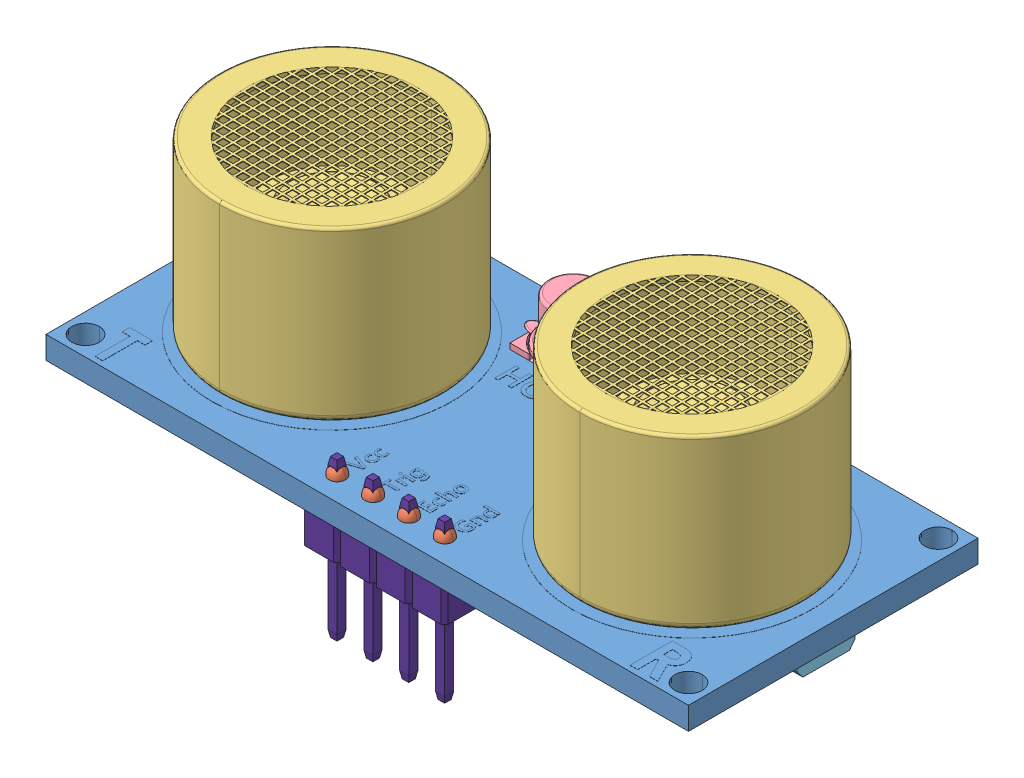
SolidWorks assembly HC-SR04, configuration Default. Lengths in mm.
Overall size (45.5 21.95 20.5).
46 component instances, 17 part files, 0 mates.
Components (placement in the parent):
- HC-SR04.STEP-1: HC-SR04.STEP [Default] at origin size (45.5 21.95 20.5)
  - HC-SR04board.STEP-1: HC-SR04board.STEP [Default] at origin size (45.5 1.61 20.5)
  - solder.STEP-1: solder.STEP [Default] at (-3.8014 1.6 8.5727) size (1.17 0.65 1.17)
  - solder.STEP-2: solder.STEP [Default] at (-1.2614 1.6 8.5727) size (1.17 0.65 1.17)
  - solder.STEP-3: solder.STEP [Default] at (1.2786 1.6 8.5727) size (1.17 0.65 1.17)
  - solder.STEP-4: solder.STEP [Default] at (3.8186 1.6 8.5727) size (1.17 0.65 1.17)
  - Emitter.STEP-1: Emitter.STEP [Default] at (-12.75 1.6 0) size (15.9 15.2 15.9)
  - Emitter.STEP-2: Emitter.STEP [Default] at (12.75 1.6 0) size (15.9 15.2 15.9)
  - CrystalOscillator.STEP-1: CrystalOscillator.STEP [Default] at (0 1.6 -7.5) size (13.3 6.4 4.5)
  - solder.STEP-5: solder.STEP [Default] at (-2.0167 0 -7.5286) x (-0.837169 0 -0.546944) z (-0.546944 0 0.837169) size (1.17 0.65 1.17)
  - solder.STEP-6: solder.STEP [Default] at (1.9833 0 -7.5286) x (-0.837169 0 -0.546944) z (-0.546944 0 0.837169) size (1.17 0.65 1.17)
  - smdChip14pin.STEP-1: smdChip14pin.STEP [Default] at (22.25 -0.725 0) x (0 0 -1) z (-1 0 0) size (7.3 1.22 8.75)
  - smdChip14pin.STEP-2: smdChip14pin.STEP [Default] at (4.375 -0.725 0) x (0 0 -1) z (-1 0 0) size (7.3 1.22 8.75)
  - smdChip16pin.STEP-1: smdChip16pin.STEP [Default] at (-18.6 -0.725 5) x (1 0 0) z (0 0 -1) size (7.3 1.22 10)
  - smdceramiccapacitor.STEP-1: smdceramiccapacitor.STEP [Default] at (17.8499 0 -5.5522) x (0 0 -1) z (-1 0 0) size (2.52 0.61 1.3)
  - smdceramiccapacitor.STEP-2: smdceramiccapacitor.STEP [Default] at (17.8499 0 5.585) x (0 0 -1) z (-1 0 0) size (2.52 0.61 1.3)
  - smdceramiccapacitor.STEP-3: smdceramiccapacitor.STEP [Default] at (15.2359 0 8.7006) x (-1 0 0) z (0 0 1) size (2.52 0.61 1.3)
  - smdceramiccapacitor.STEP-4: smdceramiccapacitor.STEP [Default] at (8.3844 0 0.0383) x (-1 0 0) z (0 0 1) size (2.52 0.61 1.3)
  - smdceramiccapacitor.STEP-5: smdceramiccapacitor.STEP [Default] at (8.3844 0 -4.7577) x (-1 0 0) z (0 0 1) size (2.52 0.61 1.3)
  - smdceramiccapacitor.STEP-6: smdceramiccapacitor.STEP [Default] at (8.3844 0 -2.3108) x (-1 0 0) z (0 0 1) size (2.52 0.61 1.3)
  - smdceramiccapacitor.STEP-7: smdceramiccapacitor.STEP [Default] at (-7.8145 0 -2.3108) x (-1 0 0) z (0 0 1) size (2.52 0.61 1.3)
  - smdResistor753.STEP-1: smdResistor753.STEP [Default] at (20.6199 0 5.0565) x (-1 0 0) z (0 0 1) size (2.53 0.63 1.31)
  - smdResistor753.STEP-2: smdResistor753.STEP [Default] at (-7.7732 0 -0.1429) x (-1 0 0) z (0 0 1) size (2.53 0.63 1.31)
  - smdResistor753.STEP-3: smdResistor753.STEP [Default] at (20.6199 0 -4.936) x (-1 0 0) z (0 0 1) size (2.53 0.63 1.31)
  - smdResistor392.STEP-1: smdResistor392.STEP [Default] at (-18.578 0 -6.4389) x (-1 0 0) z (0 0 1) size (2.53 0.63 1.31)
  - smdResistor103.STEP-1: smdResistor103.STEP [Default] at (-18.578 0 6.8031) x (-1 0 0) z (0 0 1) size (2.53 0.63 1.31)
  - smdResistor124.STEP-1: smdResistor124.STEP [Default] at (-7.7732 0 1.8639) x (-1 0 0) z (0 0 1) size (2.53 0.63 1.31)
  - smdResistor103.STEP-2: smdResistor103.STEP [Default] at (-7.7732 0 3.8148) x (-1 0 0) z (0 0 1) size (2.53 0.63 1.31)
  - smdResistor103.STEP-3: smdResistor103.STEP [Default] at (-7.7732 0 5.8773) x (-1 0 0) z (0 0 1) size (2.53 0.63 1.31)
  - smdResistor335.STEP-1: smdResistor335.STEP [Default] at (-7.7732 0 -4.435) x (-1 0 0) z (0 0 1) size (2.53 0.63 1.31)
  - smdResistor102.STEP-1: smdResistor102.STEP [Default] at (8.4383 0 5.8773) x (-1 0 0) z (0 0 1) size (2.53 0.63 1.31)
  - smdResistor103.STEP-4: smdResistor103.STEP [Default] at (8.4383 0 3.8148) x (-1 0 0) z (0 0 1) size (2.53 0.63 1.31)
  - smdResistor563.STEP-1: smdResistor563.STEP [Default] at (8.4383 0 1.8639) x (-1 0 0) z (0 0 1) size (2.53 0.63 1.31)
  - smdResistor103.STEP-5: smdResistor103.STEP [Default] at (8.4383 0 -6.6305) x (-1 0 0) z (0 0 1) size (2.53 0.63 1.31)
  - smdResistor622.STEP-1: smdResistor622.STEP [Default] at (9.6708 0 8.6421) x (-1 0 0) z (0 0 1) size (2.53 0.63 1.31)
  - smdResistor124.STEP-2: smdResistor124.STEP [Default] at (10.2038 0 -8.7291) x (-1 0 0) z (0 0 1) size (2.53 0.63 1.31)
  - smdResistor412.STEP-1: smdResistor412.STEP [Default] at (14.0013 0 -8.7291) x (-1 0 0) z (0 0 1) size (2.53 0.63 1.31)
  - smdResistor103.STEP-6: smdResistor103.STEP [Default] at (17.3324 0 -8.7291) x (-1 0 0) z (0 0 1) size (2.53 0.63 1.31)
  - solder.STEP-7: solder.STEP [Default] at (-12.8084 0 -5.0269) x (-0.837169 0 -0.546944) z (-0.546944 0 0.837169) size (1.17 0.65 1.17)
  - solder.STEP-8: solder.STEP [Default] at (-12.8084 0 5.0295) x (-0.837169 0 -0.546944) z (-0.546944 0 0.837169) size (1.17 0.65 1.17)
  - solder.STEP-9: solder.STEP [Default] at (12.7872 0 5.0295) x (-0.837169 0 -0.546944) z (-0.546944 0 0.837169) size (1.17 0.65 1.17)
  - solder.STEP-10: solder.STEP [Default] at (12.7872 0 -5.0269) x (-0.837169 0 -0.546944) z (-0.546944 0 0.837169) size (1.17 0.65 1.17)
  - headerMale.STEP-1: headerMale.STEP [Default] at (3.81 0 8.58) x (-1 0 0) z (0 0 1) size (2.54 11.1 2.54)
  - headerMale.STEP-2: headerMale.STEP [Default] at (1.27 0 8.58) x (-1 0 0) z (0 0 1) size (2.54 11.1 2.54)
  - headerMale.STEP-3: headerMale.STEP [Default] at (-1.27 0 8.58) x (-1 0 0) z (0 0 1) size (2.54 11.1 2.54)
  - headerMale.STEP-4: headerMale.STEP [Default] at (-3.81 0 8.58) x (-1 0 0) z (0 0 1) size (2.54 11.1 2.54)
